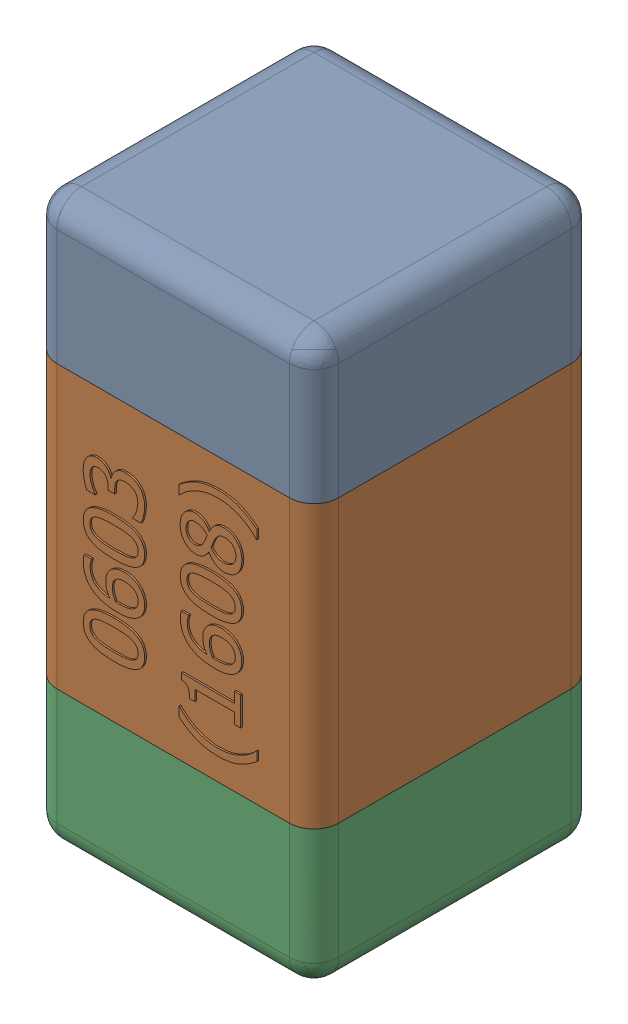
SolidWorks assembly C35, configuration Standard. Lengths in mm.
Overall size (0.81 1.61 0.81).
4 component instances, 3 part files, 0 mates.
Components (placement in the parent):
- C35-subassembly-1-1: C35-subassembly-1 [Standard] at (-9.5001 3.4001 0) x (0 1 0) z (0 0 1) size (1.61 0.81 0.81)
  - User Library-0603_Cap-1: User Library-0603_Cap [Standard] at origin size (0.41 0.81 0.81)
  - User Library-0603_Cap-1-1: User Library-0603_Cap-1 [Standard] at origin size (0.8 0.8 0.81)
  - User Library-0603_Cap-2-1: User Library-0603_Cap-2 [Standard] at origin size (0.41 0.81 0.81)
